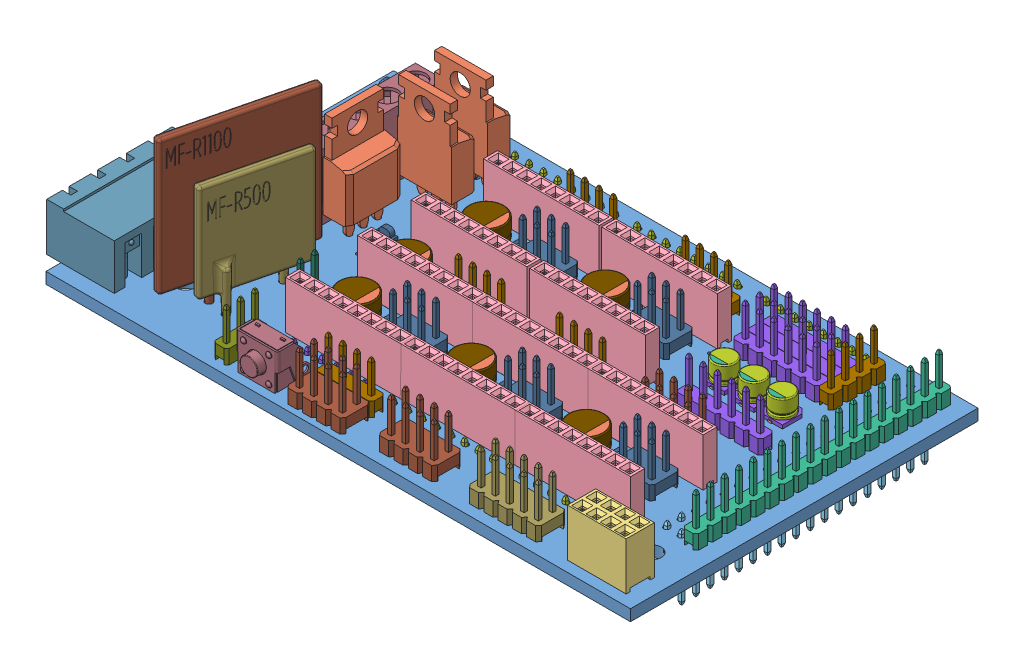
SolidWorks assembly RAMPS1_4, configuration Default. Lengths in mm.
Overall size (106.38 37.63 61.76).
107 component instances, 31 part files, 0 mates.
Components (placement in the parent):
- RAMPS1_4-1: RAMPS1_4 [Default] at (-38.4421 2.2803 -26.502) x (1 0 0) z (0 1 0) size (103.85 61.76 2)
- User Library-POWER MOSFET, NON-SURFACE-MOUNT-1: User Library-POWER MOSFET, NON-SURFACE-MOUNT [Default] at (-31.1839 8.1207 -13.4695) x (-1 0 0) z (0 -1 0) size (9.65 4.5 28.38)
- female_header_a-bl254-dg-g08d-1: female_header_a-bl254-dg-g08d [Default] at (41.0481 4.2584 25.6311) size (10.41 11.65 5)
- female_header_a-bl254-eg-g08d-1: female_header_a-bl254-eg-g08d [Default] at (6.4047 4.2963 4.0858) size (20.57 11.65 2.5)
- female_header_a-bl254-eg-g08d-2: female_header_a-bl254-eg-g08d [Default] at (6.3865 4.2963 -6.1397) size (20.57 11.65 2.5)
- female_header_a-bl254-eg-g08d-3: female_header_a-bl254-eg-g08d [Default] at (-14.6923 4.2963 -6.1397) size (20.57 11.65 2.5)
- female_header_a-bl254-eg-g08d-4: female_header_a-bl254-eg-g08d [Default] at (-14.6047 4.2963 -18.9127) size (20.57 11.65 2.5)
- female_header_a-bl254-eg-g08d-5: female_header_a-bl254-eg-g08d [Default] at (6.3788 4.2963 -18.9127) size (20.57 11.65 2.5)
- female_header_a-bl254-eg-g08d-6: female_header_a-bl254-eg-g08d [Default] at (6.414 4.2963 16.9123) size (20.57 11.65 2.5)
- female_header_a-bl254-eg-g08d-7: female_header_a-bl254-eg-g08d [Default] at (-13.9941 4.2963 16.9123) size (20.57 11.65 2.5)
- female_header_a-bl254-eg-g08d-8: female_header_a-bl254-eg-g08d [Default] at (-14.0103 4.2963 4.0799) size (20.57 11.65 2.5)
- female_header_a-bl254-eg-g08d-9: female_header_a-bl254-eg-g08d [Default] at (26.8455 4.2963 4.0799) size (20.57 11.65 2.5)
- female_header_a-bl254-eg-g08d-10: female_header_a-bl254-eg-g08d [Default] at (26.827 4.2963 16.9325) size (20.57 11.65 2.5)
- pin_header_aw254-dg-g36d-1: pin_header_aw254-dg-g36d [Default] at (40.9113 2.2239 -7.3898) x (0 0 1) z (-1 0 0) size (45.72 11.5 5.08)
- pin_header_aw140-eg-g18d-1: pin_header_aw140-eg-g18d [Default] at (44.7498 4.3175 -7.3949) x (0 0 -1) z (-1 0 0) size (45.62 11.2 2.5)
- pin_header_aw140-eg-g08d-1: pin_header_aw140-eg-g08d [Default] at (28.1033 2.2803 19.4616) size (20.22 11.2 2.5)
- pin_header_aw140-eg-g08d-2: pin_header_aw140-eg-g08d [Default] at (5.0609 2.2803 19.4616) size (20.22 11.2 2.5)
- pin_header_aw140-eg-g08d-3: pin_header_aw140-eg-g08d [Default] at (-0.0426 2.2803 -29.0108) size (20.22 11.2 2.5)
- pin_header_aw140-eg-g08d-4: pin_header_aw140-eg-g08d [Default] at (22.8713 2.2803 -29.0108) size (20.22 11.2 2.5)
- pin_header_aw140-eg-g08d-5: pin_header_aw140-eg-g08d [Default] at (-21.773 2.2803 -29.0108) size (20.22 11.2 2.5)
- pin_header_aw140-eg-g06d-1: pin_header_aw140-eg-g06d [Default] at (29.4382 4.2803 -6.1813) x (-1 0 0) z (0 0 1) size (15.14 11.2 2.5)
- pin_header_aw140-eg-g06d-2: pin_header_aw140-eg-g06d [Default] at (26.2798 4.262 -19.3796) x (-1 0 0) z (0 0 1) size (15.14 11.2 2.5)
- pin_header_aw140-eg-g06d-3: pin_header_aw140-eg-g06d [Default] at (26.2798 4.262 -21.9464) x (-1 0 0) z (0 0 1) size (15.14 11.2 2.5)
- pin_header_aw140-eg-g06d-4: pin_header_aw140-eg-g06d [Default] at (26.2798 4.262 -24.4908) x (-1 0 0) z (0 0 1) size (15.14 11.2 2.5)
- pin_header_aw140-eg-g04d-1: pin_header_aw140-eg-g04d [Default] at (8.4073 4.2803 -24.0519) x (-1 0 0) z (0 0 1) size (10.06 11.2 2.5)
- pin_header_aw140-eg-g04d-2: pin_header_aw140-eg-g04d [Default] at (-12.021 4.262 -24.0519) x (-1 0 0) z (0 0 1) size (10.06 11.2 2.5)
- pin_header_aw140-eg-g04d-3: pin_header_aw140-eg-g04d [Default] at (-8.9039 4.262 -1.0355) x (-1 0 0) z (0 0 1) size (10.06 11.2 2.5)
- pin_header_aw140-eg-g04d-4: pin_header_aw140-eg-g04d [Default] at (9.0685 4.262 -1.0355) x (-1 0 0) z (0 0 1) size (10.06 11.2 2.5)
- pin_header_aw140-eg-g04d-5: pin_header_aw140-eg-g04d [Default] at (-8.3709 4.2803 22.5944) x (-1 0 0) z (0 0 1) size (10.06 11.2 2.5)
- pin_header_aw254-dg-g06d-1: pin_header_aw254-dg-g06d [Default] at (-10.2573 4.2803 9.2323) x (-1 0 0) z (0 0 1) size (7.62 11.5 5.08)
- pin_header_aw254-dg-g06d-2: pin_header_aw254-dg-g06d [Default] at (10.1683 4.262 9.2323) x (-1 0 0) z (0 0 1) size (7.62 11.5 5.08)
- pin_header_aw254-dg-g06d-3: pin_header_aw254-dg-g06d [Default] at (30.6527 4.262 9.2323) x (-1 0 0) z (0 0 1) size (7.62 11.5 5.08)
- pin_header_aw254-dg-g06d-4: pin_header_aw254-dg-g06d [Default] at (10.1683 4.262 -13.7827) x (-1 0 0) z (0 0 1) size (7.62 11.5 5.08)
- pin_header_aw254-dg-g06d-5: pin_header_aw254-dg-g06d [Default] at (-10.2204 4.262 -13.7827) x (-1 0 0) z (0 0 1) size (7.62 11.5 5.08)
- pin_header_aw254-dg-g08d-1: pin_header_aw254-dg-g08d [Default] at (7.0775 4.2803 25.6017) x (-1 0 0) z (0 0 1) size (10.16 11.5 5.08)
- pin_header_aw254-dg-g08d-2: pin_header_aw254-dg-g08d [Default] at (-8.3884 4.2803 26.4286) x (-1 0 0) z (0 0 1) size (10.16 11.5 5.08)
- pin_header_aw254-dg-g10d-1: pin_header_aw254-dg-g10d [Default] at (24.3252 4.2803 25.6162) x (-1 0 0) z (0 0 1) size (12.7 11.5 5.08)
- pin_header_aw140-eg-g04d-6: pin_header_aw140-eg-g04d [Default] at (35.1498 4.262 -23.186) x (0 0 -1) z (-1 0 0) size (10.06 11.2 2.5)
- pin_header_aw140-eg-g06d-5: pin_header_aw140-eg-g06d [Default] at (-15.2568 2.2803 19.3514) size (15.14 11.2 2.5)
- terminal_blocks_a-tb500-to06-1: terminal_blocks_a-tb500-to06 [Default] at (-37.528 4.2803 -9.8658) x (0 0 1) z (-1 0 0) size (30.6 13.8 8.3)
- terminal_blocks_a-tb508-oq04ch-1: terminal_blocks_a-tb508-oq04ch [Default] at (-57.4712 4.2803 16.3679) x (0 0 1) z (-1 0 0) size (22.32 12.5 12)
- pin_header_aw254-dg-g08d-3: pin_header_aw254-dg-g08d [Default] at (26.8817 4.262 0.2918) x (-1 0 0) z (0 0 1) size (10.16 11.5 5.08)
- pin_header_aw140-eg-g02d-1: pin_header_aw140-eg-g02d [Default] at (-26.0896 4.2803 12.3888) x (0 0 1) z (1 0 0) size (4.98 11.2 2.5)
- pin_header_aw140-eg-g03d-1: pin_header_aw140-eg-g03d [Default] at (-25.5036 4.2803 24.8649) x (0 0 1) z (1 0 0) size (7.52 11.2 2.5)
- User Library-CAPSMD6_3x3_9-1: User Library-CAPSMD6_3x3_9 [Default] at (-23.4034 4.2803 -13.8521) x (0 0 -1) z (0 1 0) size (6.6 7 3.91)
  - User Library-CAPSMD6_3x3_9_CAP003-1: User Library-CAPSMD6_3x3_9_CAP003 [Default] at origin size (0.65 2.6 0.32)
  - User Library-CAPSMD6_3x3_9_CAP-1: User Library-CAPSMD6_3x3_9_CAP [Default] at origin size (6.3 6.3 3.26)
  - User Library-CAPSMD6_3x3_9_CAP001-1: User Library-CAPSMD6_3x3_9_CAP001 [Default] at origin size (6.6 6.6 0.64)
  - User Library-CAPSMD6_3x3_9_CAP002-1: User Library-CAPSMD6_3x3_9_CAP002 [Default] at origin size (5.11 1.47 0.01)
  - User Library-CAPSMD6_3x3_9_CAP004-1: User Library-CAPSMD6_3x3_9_CAP004 [Default] at origin size (0.65 2.6 0.32)
- User Library-CAPSMD6_3x3_9-2: User Library-CAPSMD6_3x3_9 [Default] at (-2.2688 4.2803 -13.8521) x (0 0 -1) z (0 1 0) size (6.6 7 3.91)
  - User Library-CAPSMD6_3x3_9_CAP003-1: User Library-CAPSMD6_3x3_9_CAP003 [Default] at origin size (0.65 2.6 0.32)
  - User Library-CAPSMD6_3x3_9_CAP-1: User Library-CAPSMD6_3x3_9_CAP [Default] at origin size (6.3 6.3 3.26)
  - User Library-CAPSMD6_3x3_9_CAP001-1: User Library-CAPSMD6_3x3_9_CAP001 [Default] at origin size (6.6 6.6 0.64)
  - User Library-CAPSMD6_3x3_9_CAP002-1: User Library-CAPSMD6_3x3_9_CAP002 [Default] at origin size (5.11 1.47 0.01)
  - User Library-CAPSMD6_3x3_9_CAP004-1: User Library-CAPSMD6_3x3_9_CAP004 [Default] at origin size (0.65 2.6 0.32)
- User Library-CAPSMD6_3x3_9-3: User Library-CAPSMD6_3x3_9 [Default] at (-2.8787 4.2803 9.2865) x (0 0 -1) z (0 1 0) size (6.6 7 3.91)
  - User Library-CAPSMD6_3x3_9_CAP003-1: User Library-CAPSMD6_3x3_9_CAP003 [Default] at origin size (0.65 2.6 0.32)
  - User Library-CAPSMD6_3x3_9_CAP-1: User Library-CAPSMD6_3x3_9_CAP [Default] at origin size (6.3 6.3 3.26)
  - User Library-CAPSMD6_3x3_9_CAP001-1: User Library-CAPSMD6_3x3_9_CAP001 [Default] at origin size (6.6 6.6 0.64)
  - User Library-CAPSMD6_3x3_9_CAP002-1: User Library-CAPSMD6_3x3_9_CAP002 [Default] at origin size (5.11 1.47 0.01)
  - User Library-CAPSMD6_3x3_9_CAP004-1: User Library-CAPSMD6_3x3_9_CAP004 [Default] at origin size (0.65 2.6 0.32)
- User Library-CAPSMD6_3x3_9-4: User Library-CAPSMD6_3x3_9 [Default] at (-23.2996 4.2803 9.2865) x (0 0 -1) z (0 1 0) size (6.6 7 3.91)
  - User Library-CAPSMD6_3x3_9_CAP003-1: User Library-CAPSMD6_3x3_9_CAP003 [Default] at origin size (0.65 2.6 0.32)
  - User Library-CAPSMD6_3x3_9_CAP-1: User Library-CAPSMD6_3x3_9_CAP [Default] at origin size (6.3 6.3 3.26)
  - User Library-CAPSMD6_3x3_9_CAP001-1: User Library-CAPSMD6_3x3_9_CAP001 [Default] at origin size (6.6 6.6 0.64)
  - User Library-CAPSMD6_3x3_9_CAP002-1: User Library-CAPSMD6_3x3_9_CAP002 [Default] at origin size (5.11 1.47 0.01)
  - User Library-CAPSMD6_3x3_9_CAP004-1: User Library-CAPSMD6_3x3_9_CAP004 [Default] at origin size (0.65 2.6 0.32)
- User Library-CAPSMD6_3x3_9-5: User Library-CAPSMD6_3x3_9 [Default] at (17.5196 4.2803 9.2865) x (0 0 -1) z (0 1 0) size (6.6 7 3.91)
  - User Library-CAPSMD6_3x3_9_CAP003-1: User Library-CAPSMD6_3x3_9_CAP003 [Default] at origin size (0.65 2.6 0.32)
  - User Library-CAPSMD6_3x3_9_CAP-1: User Library-CAPSMD6_3x3_9_CAP [Default] at origin size (6.3 6.3 3.26)
  - User Library-CAPSMD6_3x3_9_CAP001-1: User Library-CAPSMD6_3x3_9_CAP001 [Default] at origin size (6.6 6.6 0.64)
  - User Library-CAPSMD6_3x3_9_CAP002-1: User Library-CAPSMD6_3x3_9_CAP002 [Default] at origin size (5.11 1.47 0.01)
  - User Library-CAPSMD6_3x3_9_CAP004-1: User Library-CAPSMD6_3x3_9_CAP004 [Default] at origin size (0.65 2.6 0.32)
- User Library-CAPSMD6_3x3_9-6: User Library-CAPSMD6_3x3_9 [Default] at (-24.6073 4.2803 -1.0117) x (0 0 -1) z (0 1 0) size (6.6 7 3.91)
  - User Library-CAPSMD6_3x3_9_CAP003-1: User Library-CAPSMD6_3x3_9_CAP003 [Default] at origin size (0.65 2.6 0.32)
  - User Library-CAPSMD6_3x3_9_CAP-1: User Library-CAPSMD6_3x3_9_CAP [Default] at origin size (6.3 6.3 3.26)
  - User Library-CAPSMD6_3x3_9_CAP001-1: User Library-CAPSMD6_3x3_9_CAP001 [Default] at origin size (6.6 6.6 0.64)
  - User Library-CAPSMD6_3x3_9_CAP002-1: User Library-CAPSMD6_3x3_9_CAP002 [Default] at origin size (5.11 1.47 0.01)
  - User Library-CAPSMD6_3x3_9_CAP004-1: User Library-CAPSMD6_3x3_9_CAP004 [Default] at origin size (0.65 2.6 0.32)
- User Library-CAPSMD4x3_9-1: User Library-CAPSMD4x3_9 [Default] at (22.2937 4.2803 -15.1178) x (1 0 0) z (0 1 0) size (4.3 4.6 3.91)
  - User Library-CAPSMD4x3_9_CAPSMD4x3_9003-1: User Library-CAPSMD4x3_9_CAPSMD4x3_9003 [Default] at origin size (0.65 1.8 0.32)
  - User Library-CAPSMD4x3_9_CAPSMD4x3_9004-1: User Library-CAPSMD4x3_9_CAPSMD4x3_9004 [Default] at origin size (0.65 1.8 0.32)
  - User Library-CAPSMD4x3_9_CAPSMD4x3_9002-1: User Library-CAPSMD4x3_9_CAPSMD4x3_9002 [Default] at origin size (3.12 0.9 0.01)
  - User Library-CAPSMD4x3_9_CAPSMD4x3_9001-1: User Library-CAPSMD4x3_9_CAPSMD4x3_9001 [Default] at origin size (4 4 3.26)
  - User Library-CAPSMD4x3_9_CAPSMD4x3_9-1: User Library-CAPSMD4x3_9_CAPSMD4x3_9 [Default] at origin size (4.3 4.3 0.64)
- User Library-CAPSMD4x3_9-2: User Library-CAPSMD4x3_9 [Default] at (27.5508 4.2803 -15.1178) x (1 0 0) z (0 1 0) size (4.3 4.6 3.91)
  - User Library-CAPSMD4x3_9_CAPSMD4x3_9003-1: User Library-CAPSMD4x3_9_CAPSMD4x3_9003 [Default] at origin size (0.65 1.8 0.32)
  - User Library-CAPSMD4x3_9_CAPSMD4x3_9004-1: User Library-CAPSMD4x3_9_CAPSMD4x3_9004 [Default] at origin size (0.65 1.8 0.32)
  - User Library-CAPSMD4x3_9_CAPSMD4x3_9002-1: User Library-CAPSMD4x3_9_CAPSMD4x3_9002 [Default] at origin size (3.12 0.9 0.01)
  - User Library-CAPSMD4x3_9_CAPSMD4x3_9001-1: User Library-CAPSMD4x3_9_CAPSMD4x3_9001 [Default] at origin size (4 4 3.26)
  - User Library-CAPSMD4x3_9_CAPSMD4x3_9-1: User Library-CAPSMD4x3_9_CAPSMD4x3_9 [Default] at origin size (4.3 4.3 0.64)
- User Library-CAPSMD4x3_9-3: User Library-CAPSMD4x3_9 [Default] at (32.6212 4.2803 -15.1178) x (1 0 0) z (0 1 0) size (4.3 4.6 3.91)
  - User Library-CAPSMD4x3_9_CAPSMD4x3_9003-1: User Library-CAPSMD4x3_9_CAPSMD4x3_9003 [Default] at origin size (0.65 1.8 0.32)
  - User Library-CAPSMD4x3_9_CAPSMD4x3_9004-1: User Library-CAPSMD4x3_9_CAPSMD4x3_9004 [Default] at origin size (0.65 1.8 0.32)
  - User Library-CAPSMD4x3_9_CAPSMD4x3_9002-1: User Library-CAPSMD4x3_9_CAPSMD4x3_9002 [Default] at origin size (3.12 0.9 0.01)
  - User Library-CAPSMD4x3_9_CAPSMD4x3_9001-1: User Library-CAPSMD4x3_9_CAPSMD4x3_9001 [Default] at origin size (4 4 3.26)
  - User Library-CAPSMD4x3_9_CAPSMD4x3_9-1: User Library-CAPSMD4x3_9_CAPSMD4x3_9 [Default] at origin size (4.3 4.3 0.64)
- User Library-APA3010GCCK_GREEN-1: User Library-APA3010GCCK_GREEN [Default] at (-34.2243 4.3303 -27.7242) x (0 0 1) z (-1 0 0) size (3 2 1)
- User Library-APA3010GCCK_RED-1: User Library-APA3010GCCK_RED [Default] at (-49.6191 4.3303 -27.7242) x (0 0 1) z (-1 0 0) size (3 2 1)
- User Library-APA3010GCCK_RED-2: User Library-APA3010GCCK_RED [Default] at (-52.1602 4.3303 -27.7242) x (0 0 1) z (-1 0 0) size (3 2 1)
- User Library-MF-R1100___ _________-1: User Library-MF-R1100___ _________ [Default] at (-35.7942 -0.3428 15.0699) x (0 0 -1) z (0 -1 0) size (23.64 7.06 35.7)
- User Library-MF-R500___ _________-1: User Library-MF-R500___ _________ [Default] at (-32.5552 -0.5896 15.3075) x (0 0 -1) z (0 -1 0) size (17.04 5.43 29.1)
- User Library-SWITCH, TACTILE, RIGHT ANGLE, 12VDC, 50MA, 6_85MM ACTUATOR, WEALTH METAL TC-0244Z-1: User Library-SWITCH, TACTILE, RIGHT ANGLE, 12VDC, 50MA, 6_85MM ACTUATOR, WEALTH METAL TC-0244Z [Default] at (-19.0613 3.9803 23.5512) size (7.4 11 8)
- User Library-APA3010GCCK_RED-3: User Library-APA3010GCCK_RED [Default] at (-29.5185 4.3303 -5.1301) size (3 2 1)
- User Library-POWER MOSFET, NON-SURFACE-MOUNT-2: User Library-POWER MOSFET, NON-SURFACE-MOUNT [Default] at (-31.3941 8.433 -20.0341) x (-1 0 0) z (0 -1 0) size (9.65 4.5 28.38)
- User Library-POWER MOSFET, NON-SURFACE-MOUNT-3: User Library-POWER MOSFET, NON-SURFACE-MOUNT [Default] at (-36.1067 8.2823 -5.2135) x (0 0 -1) z (0 -1 0) size (9.65 4.5 28.38)
